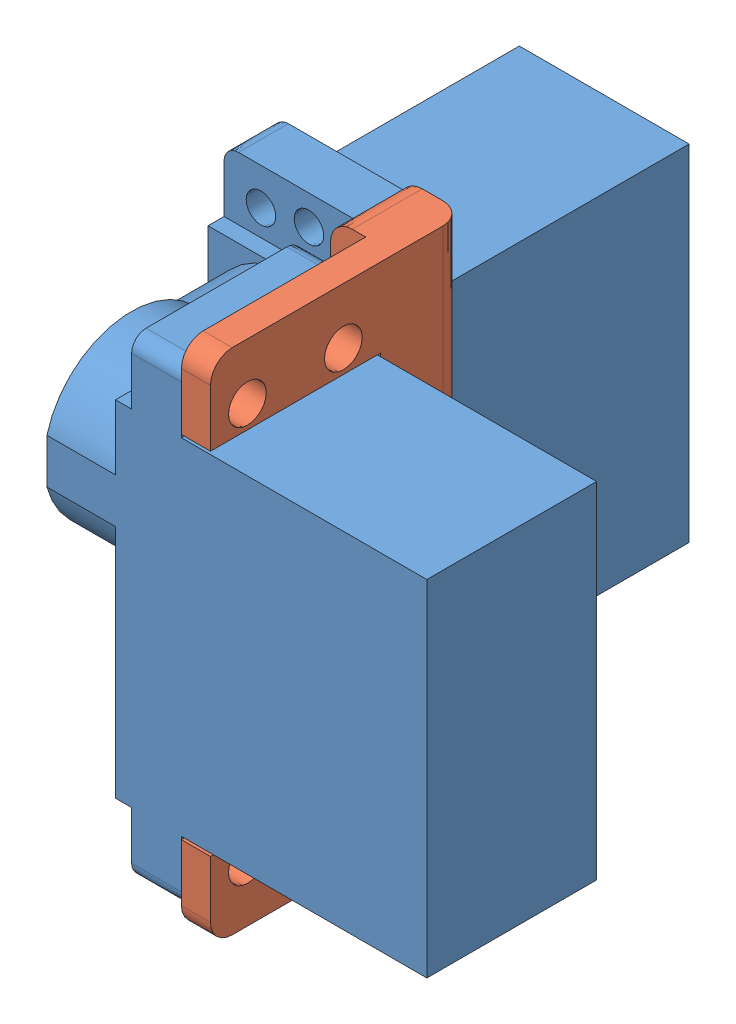
SolidWorks assembly assemblage pantilt, configuration Défaut. Lengths in mm.
Overall size (34.47 39.55 40.83).
3 component instances, 2 part files, 5 mates.
Components (placement in the parent):
- servo-1: servo [Défaut] at (-2258.0003 -328.6111 -461.3814) x (0 0 -1) z (1 0 0) size (26.15 32.39 11.68)
- servo-2: servo [Défaut] at (-2244.9552 -322.7564 -453.657) size (26.15 32.39 11.68)
- pantilt-2: pantilt [Défaut] at (-2240.4228 -305.2864 -485.3214) x (0 0 -1) z (1 0 0) size (17.5 35 17.32)
Mates (geometry in assembly coordinates):
- Coïncidente1: coincident anti-aligned: plane of servo-2 through (-2240.4228 -294.6894 -453.657) normal (1 0 0); plane of pantilt-2 through (-2240.4228 -328.3819 -441.973) normal (-1 0 0)
- Coïncidente3: coincident aligned: plane of servo-2 through (-2244.9552 -299.0074 -441.973) normal (0 0 1); plane of pantilt-2 through (-2238.4228 -293.3819 -441.973) normal (0 0 1)
- Distance2: distance = 1.3075 mm aligned: plane of servo-2 through (-2243.8518 -327.0744 -441.973) normal (0 -1 0); plane of pantilt-2 through (-2238.4228 -328.3819 -441.973) normal (0 -1 0)
- Coïncidente6: coincident anti-aligned: plane of servo-1 through (-2252.1357 -310.8819 -456.657) normal (0 0 1); plane of pantilt-2 through (-2249.1357 -293.3819 -456.657) normal (0 0 -1)
- Coaxiale1: concentric anti-aligned: circle of servo-1; circle of pantilt-2
